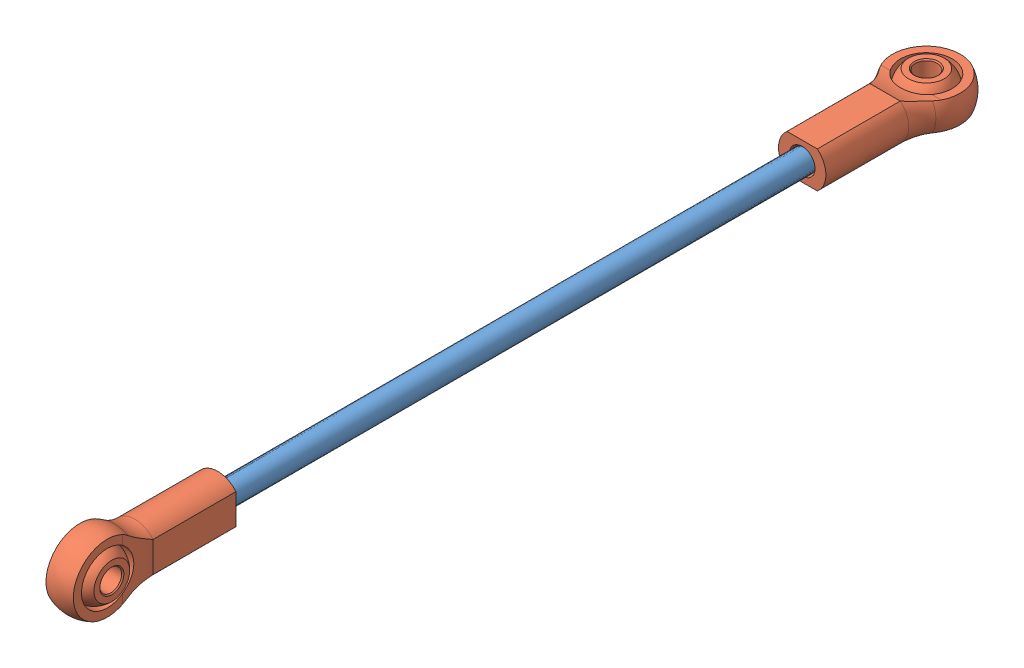
SolidWorks assembly Back suspension assembly, configuration Default. Lengths in mm.
Overall size (15.88 15.88 196.85).
3 component instances, 2 part files, 5 mates.
Components (placement in the parent):
- 6in 10-32 threaded rod-1: 6in 10-32 threaded rod [Default] at (59.1522 88.4935 33.4954) size (4.83 4.83 152.4)
- 60645K311_STEEL BALL JOINT ROD END 10-32-1: 60645K311_STEEL BALL JOINT ROD END 10-32 [60645K311] at (59.1522 88.4935 33.4954) x (1 0 0) z (0 1 0) size (15.88 34.93 10.12)
- 60645K311_STEEL BALL JOINT ROD END 10-32-2: 60645K311_STEEL BALL JOINT ROD END 10-32 [60645K311] at (59.1522 88.4935 185.8954) x (0 -1 0) z (-1 0 0) size (15.88 34.93 10.12)
Mates (geometry in assembly coordinates):
- Coincident1: coincident anti-aligned: plane of 6in 10-32 threaded rod-1 through (59.1522 88.4935 33.4954) normal (0 0 -1); plane of 60645K311_STEEL BALL JOINT ROD END 10-32-1 through (61.5652 88.4935 33.4954) normal (0 0 1)
- Concentric1: concentric aligned: circle of 6in 10-32 threaded rod-1; circle of 60645K311_STEEL BALL JOINT ROD END 10-32-1
- Coincident2: coincident anti-aligned: plane of 6in 10-32 threaded rod-1 through (59.1522 88.4935 185.8954) normal (0 0 1); plane of 60645K311_STEEL BALL JOINT ROD END 10-32-2 through (59.1522 86.0805 185.8954) normal (0 0 -1)
- Concentric2: concentric anti-aligned: circle of 6in 10-32 threaded rod-1; circle of 60645K311_STEEL BALL JOINT ROD END 10-32-2
- Angle1: planar angle = 1.570796 rad aligned: plane of 60645K311_STEEL BALL JOINT ROD END 10-32-2 through (55.1898 92.4559 191.2068) normal (-1 0 0); plane of 60645K311_STEEL BALL JOINT ROD END 10-32-1 through (55.1898 84.5311 28.184) normal (0 -1 0)
